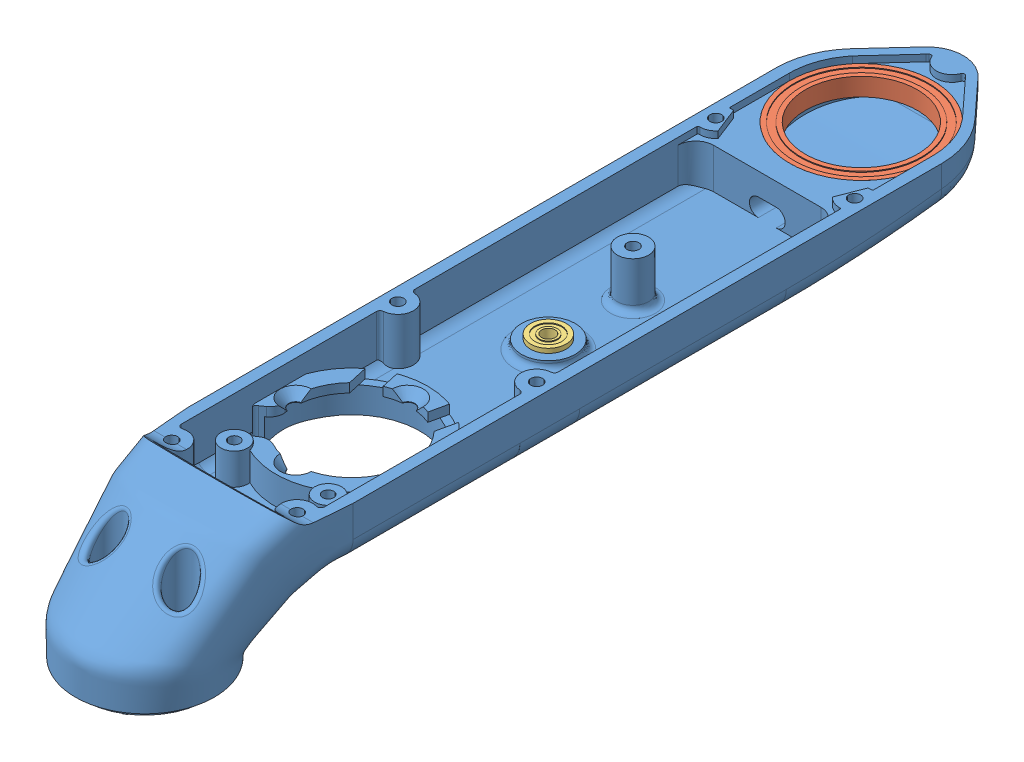
SolidWorks assembly upper limb base, configuration Default. Lengths in mm.
Overall size (48.51 37.5 198.25).
3 component instances, 3 part files, 4 mates.
Components (placement in the parent):
- upper leg module shell base-1: upper leg module shell base [Default] x (-1 0 0) z (0 0 -1) size (48.51 37.5 198.25)
- bearing 32x25x4mm-1: bearing 32x25x4mm [Default] at (0 0.5 -61) x (0.90658 0 0.422034) z (-0.422034 0 0.90658) size (32 4 32)
- bearing 8mm x 3mm x 3mm-1: bearing 8mm x 3mm x 3mm [Default] at (0 -1.5 8.9) x (1 0 0) z (0 -1 0) size (7.96 7.96 3)
Mates (geometry in assembly coordinates):
- Concentric1: concentric anti-aligned: cylinder of upper leg module shell base-1 through (0 0.5 -61) axis (0 1 0) radius 16; cylinder of bearing 32x25x4mm-1 through (0 4.5 -61) axis (0 -1 0) radius 16
- Coincident1: coincident anti-aligned: plane of upper leg module shell base-1 through (0 0.5 -61) normal (0 1 0); plane of bearing 32x25x4mm-1 through (0 0.5 -61) normal (0 -1 0)
- Coincident2: coincident anti-aligned: plane of upper leg module shell base-1 through (-13.5 -4.5 -40) normal (0 1 0); plane of bearing 8mm x 3mm x 3mm-1 through (0 -4.5 8.9) normal (0 -1 0)
- Concentric2: concentric anti-aligned: cylinder of upper leg module shell base-1 through (0 -2.5 8.9) axis (0 -1 0) radius 3.98; cylinder of bearing 8mm x 3mm x 3mm-1 through (0 -4.5 8.9) axis (0 1 0) radius 3.98
